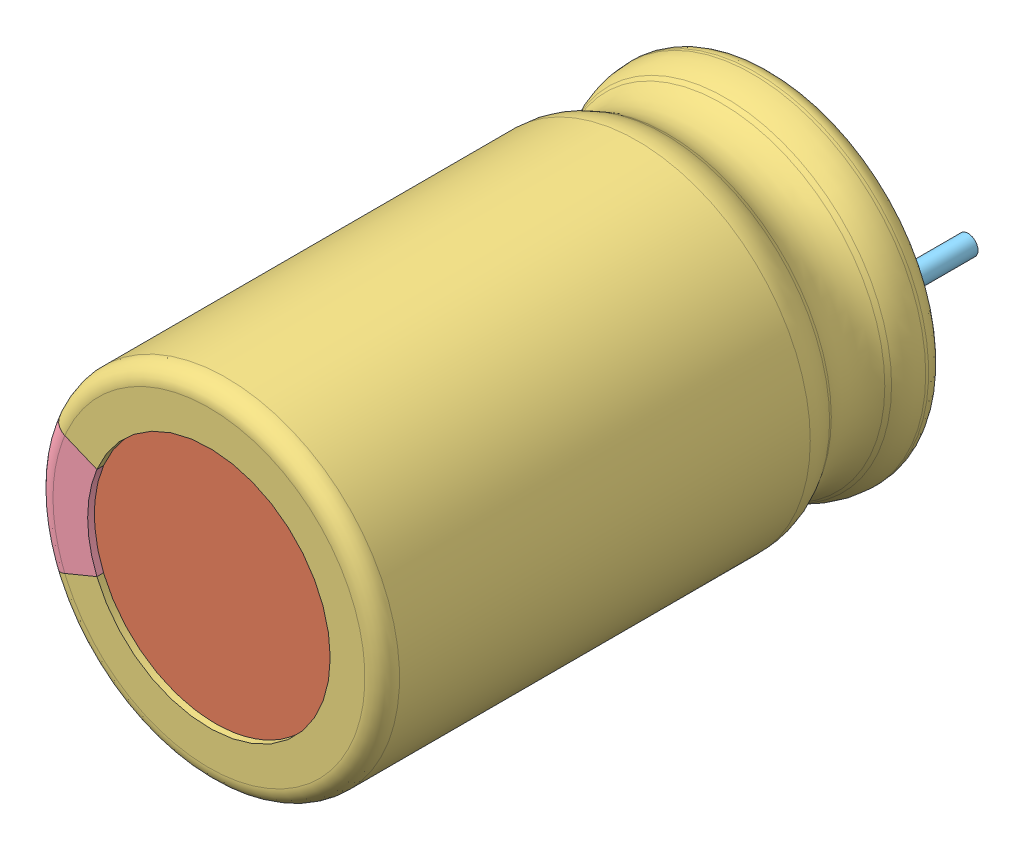
SolidWorks assembly User Library-CapAluRadial_D100H160, configuration Default. Lengths in mm.
Overall size (10.5 10.5 20.53).
6 component instances, 5 part files, 0 mates.
Components (placement in the parent):
- User Library-CapAluRadial_D100H160_rubber_pad-1: User Library-CapAluRadial_D100H160_rubber_pad [Default] at origin size (7.35 7.35 1)
- User Library-CapAluRadial_D100H160_can-1: User Library-CapAluRadial_D100H160_can [Default] at origin size (7.35 7.35 16.3)
- User Library-CapAluRadial_D100H160_shell_and_minus-1: User Library-CapAluRadial_D100H160_shell_and_minus [Default] at origin size (10.19 10.5 17.14)
- User Library-CapAluRadial_D100H160_shell_and_minus_2-1: User Library-CapAluRadial_D100H160_shell_and_minus_2 [Default] at origin size (1.86 4.3 17.14)
- User Library-CapAluRadial_D100H160_lead-1: User Library-CapAluRadial_D100H160_lead [Default] at (-2.5 0 0) size (0.6 0.6 3)
- User Library-CapAluRadial_D100H160_lead-2: User Library-CapAluRadial_D100H160_lead [Default] at (2.5 0 0) x (-1 0 0) z (0 0 1) size (0.6 0.6 3)
